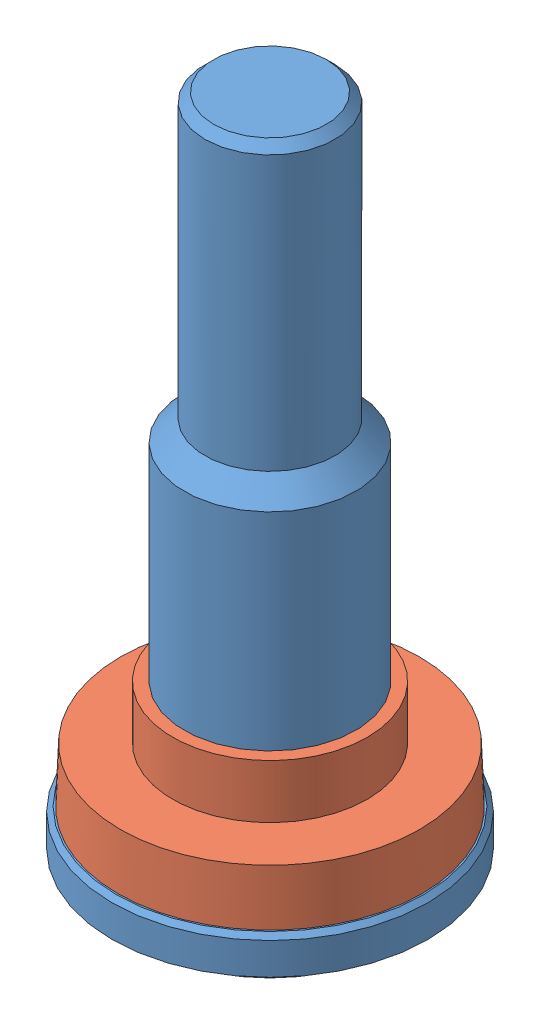
SolidWorks assembly CKAuto TR416 Metal Valve Stem, configuration Default. Lengths in mm.
Overall size (18.52 40.06 18.52).
2 component instances, 2 part files, 5 mates.
Components (placement in the parent):
- CKAuto TR416 Metal Valve Base-2: CKAuto TR416 Metal Valve Base [Default] at origin size (18.52 40.06 18.52)
- Part12^CKAuto TR416 Metal Valve Stem-1: Part12^CKAuto TR416 Metal Valve Stem [Default] x (0 0 -1) z (1 0 0) size (17.78 7.25 17.78) (virtual)
Mates (geometry in assembly coordinates):
- Coincident1: coordinate: point of CKAuto TR416 Metal Valve Base-2
- InPlace1: in place: plane of Part12^CKAuto TR416 Metal Valve Stem-1 through (0 0 0) normal (1 0 0); moOrthogonalPlaneRef_w of Part12^CKAuto TR416 Metal Valve Stem-1 through (0 0 0) normal (0 1 0); plane of Part12^CKAuto TR416 Metal Valve Stem-1 through (0 0 0) normal (0 0 -1); unknown of Part12^CKAuto TR416 Metal Valve Stem-1
- Coincident2: coincident aligned: 
- Coincident3: coincident aligned: plane of Part12^Assem4-1 through (0 0 0) normal (0 1 0)
- Coincident4: coincident anti-aligned: plane of Part12^Assem4-1 through (0 0 0) normal (0 0 -1)
